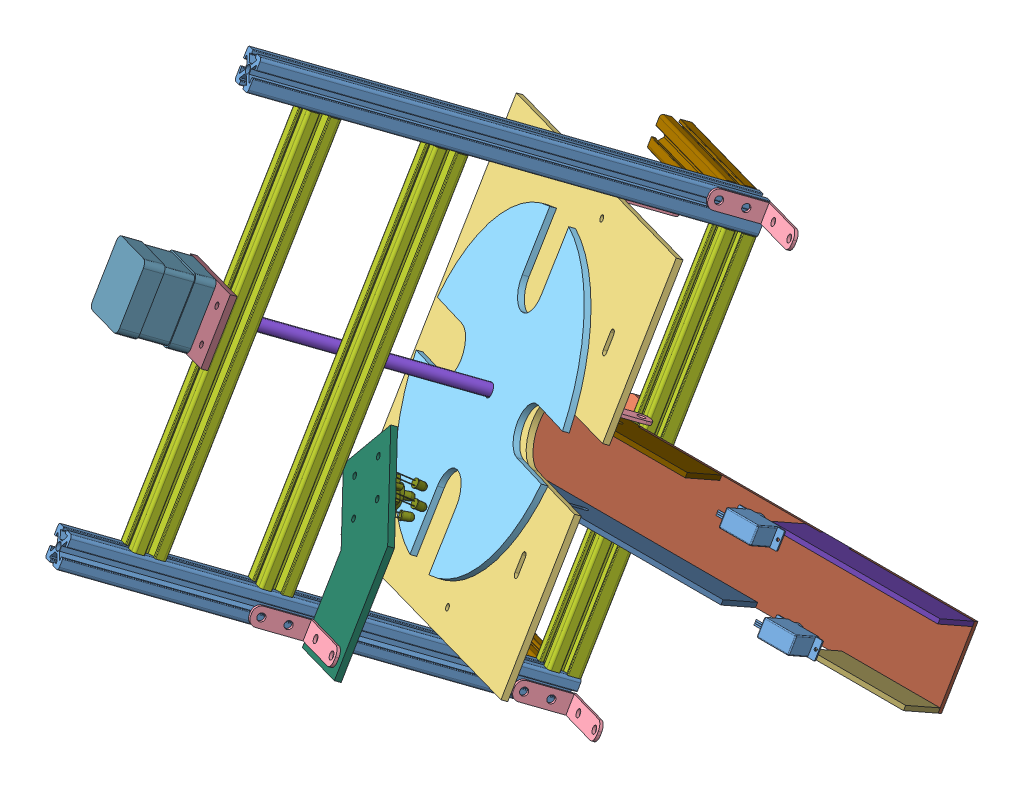
SolidWorks assembly Assem1, configuration Default. Lengths in mm.
Overall size (461.85 412.05 422.92).
30 component instances, 19 part files, 80 mates.
Components (placement in the parent):
- Nhom20x20x300-1: Nhom20x20x300 [Default] at (169.8417 109.2199 41.4005) x (-0.008301 -0.865395 0.501021) z (0.475419 -0.444204 -0.759381) size (20 20 300)
- Nhom20x20x300-2: Nhom20x20x300 [Default] at (171.9169 325.5687 -83.8548) x (-0.87972 -0.231892 -0.415113) z (0.475419 -0.444204 -0.759381) size (20 20 300)
- vongbi8mm-1: vongbi8mm [Default] at (293.7185 78.9174 -258.378) x (0.008301 0.865395 -0.501021) z (-0.475419 0.444204 0.759381) size (55 36 13)
- Part2-1: Part2 [Default] at (265.9386 118.0379 -191.2668) x (0.008301 0.865395 -0.501021) z (0.475419 -0.444204 -0.759381) size (250 250 4)
- Part3-3: Part3 [Default] at (266.9894 27.5581 -142.9497) x (-0.87972 -0.231892 -0.415113) z (0.475419 -0.444204 -0.759381) size (12 45 35)
- Part3-4: Part3 [Default] at (268.6911 204.9641 -245.659) x (0.87972 0.231892 0.415113) z (0.475419 -0.444204 -0.759381) size (12 45 35)
- Part1-1: Part1 [Default] at (238.4466 113.7027 -198.0415) x (0.879597 0.223435 0.419983) z (-0.475419 0.444204 0.759381) size (197.74 197.74 4)
- khop noi 5-8-1: khop noi 5-8 [Default] at (155.0404 192.1469 -65.0985) x (0.878303 0.289288 0.380651) z (0.475419 -0.444204 -0.759381) size (19.99 20 25)
- Nhom20x20x250-4: Nhom20x20x250 [Default] at (171.3298 305.0403 -119.3225) x (0.475419 -0.444204 -0.759381) z (-0.008301 -0.865395 0.501021) size (20 20 250)
- Part9-1: Part9 [Default] at (280.0757 75.3212 -264.8156) x (0.879293 0.211818 0.426587) z (-0.475419 0.444204 0.759381) size (8 8 250)
- Nhom20x20-3: Nhom20x20 [Default] at (197.2267 -60.2922 -211.0192) x (0.475419 -0.444204 -0.759381) z (0.87972 0.231892 0.415113) size (20 20 100)
- Nhom20x20-4: Nhom20x20 [Default] at (208.9763 164.4804 -361.4825) x (0.008301 0.865395 -0.501021) z (0.87972 0.231892 0.415113) size (20 20 100)
- Part3-10: Part3 [Default] at (321.9637 86.9359 -143.2658) x (0.87972 0.231892 0.415113) z (0.475419 -0.444204 -0.759381) size (12 45 35)
- Part3-13: Part3 [Default] at (322.8021 174.3408 -193.8689) x (-0.87972 -0.231892 -0.415113) z (0.475419 -0.444204 -0.759381) size (12 45 35)
- Part11-5: Part11 [Default] at (325.071 102.927 -166.4895) x (0.99957 -0.021278 -0.020192) z (-0.008301 -0.865395 0.501021) size (170 33 3)
- Part13-1: Part13 [Default] at (424.7125 111.6918 -195.6058) x (0.99957 -0.021278 -0.020192) z (0.028135 0.500638 0.865199) size (300 52 3)
- Part7-1: Part7 [Default] at (514.5672 91.3746 -183.304) x (0.99957 -0.021278 -0.020192) z (-0.008301 -0.865395 0.501021) size (70 33 3)
- Nhom20x20x250-5: Nhom20x20x250 [Default] at (206.8913 271.8136 -176.1245) x (0.475419 -0.444204 -0.759381) z (-0.008301 -0.865395 0.501021) size (20 20 250)
- Part3-14: Part3 [Default] at (334.4526 209.6405 -309.3432) x (-0.008301 -0.865395 0.501021) z (-0.475419 0.444204 0.759381) size (12 45 35)
- Part3-15: Part3 [Default] at (332.145 -30.9393 -170.0593) x (-0.008301 -0.865395 0.501021) z (-0.475419 0.444204 0.759381) size (12 45 35)
- Nhom20x20x250-6: Nhom20x20x250 [Default] at (296.9483 187.6696 -319.9712) x (0.87972 0.231892 0.415113) z (-0.008301 -0.865395 0.501021) size (20 20 250)
- Part8-2: Part8 [Default] at (152.5555 194.4686 -61.1294) x (-0.008301 -0.865395 0.501021) z (0.475419 -0.444204 -0.759381) size (42 62 4)
- Step1-2: Step1 [Default] at (132.5879 213.1252 -29.2354) x (0.008301 0.865395 -0.501021) z (0.475419 -0.444204 -0.759381) size (42 42 57)
- ban-2: ban [Default] at (232.1754 107.3064 -115.1813) x (-0.627926 -0.775899 0.060746) z (-0.475419 0.444204 0.759381) size (89.14 124.49 4)
- TCS3200 Sensor-3: TCS3200 Sensor [Default] at (241.4182 100.5871 -105.4642) x (0.616187 -0.447955 0.647805) z (0.627926 0.775899 -0.060746) size (33 28.07 33)
- Part3-16: Part3 [Default] at (258.6403 37.7392 -52.6514) x (-0.008301 -0.865395 0.501021) z (-0.475419 0.444204 0.759381) size (12 45 35)
- Part17-1: Part17 [Default] at (490.3505 140.8192 -196.1017) x (0.99957 -0.021278 -0.020192) z (-0.008301 -0.865395 0.501021) size (120 33 3)
- Part19-2: Part19 [Default] at (325.4778 145.3314 -191.0396) x (0.99957 -0.021278 -0.020192) z (-0.008301 -0.865395 0.501021) size (120 33 3)
- Hitec HS-55 Servo-6: Hitec HS-55 Servo [Default] at (499.0255 114.2412 -149.6535) x (0.008301 0.865395 -0.501021) z (-0.99957 0.021278 0.020192) size (11.6 27 33.7)
- Hitec HS-55 Servo-7: Hitec HS-55 Servo [Default] at (452.1716 150.2077 -168.9415) x (0.008301 0.865395 -0.501021) z (-0.99957 0.021278 0.020192) size (11.6 27 33.7)
Mates (geometry in assembly coordinates):
- Coincident35: coincident anti-aligned: plane of Nhom20x20x300-1 through (300.7606 -27.1272 -191.9378) normal (0.008301 0.865395 -0.501021); plane of Part2-1 through (178.8307 -15.1025 -173.188) normal (-0.008301 -0.865395 0.501021)
- Concentric5: concentric aligned: circle of Part2-1; circle of Part3-3
- Concentric6: concentric aligned: circle of Part2-1; circle of Part3-3
- Coincident45: coincident anti-aligned: plane of Part2-1 through (267.8403 116.2611 -194.3043) normal (0.475419 -0.444204 -0.759381); plane of Part3-3 through (266.9894 27.5581 -142.9497) normal (-0.475419 0.444204 0.759381)
- Coincident46: coincident anti-aligned: plane of Nhom20x20x300-1 through (310.708 -24.5051 -187.2439) normal (0.008301 0.865395 -0.501021); plane of Part3-3 through (262.4752 5.8069 -135.6861) normal (-0.008301 -0.865395 0.501021)
- Concentric7: concentric aligned: circle of Part2-1; circle of Part3-4
- Concentric8: concentric aligned: circle of Part2-1; circle of Part3-4
- Coincident47: coincident anti-aligned: plane of Part2-1 through (267.8403 116.2611 -194.3043) normal (0.475419 -0.444204 -0.759381); plane of Part3-4 through (268.6911 204.9641 -245.659) normal (-0.475419 0.444204 0.759381)
- Coincident48: coincident anti-aligned: plane of Nhom20x20x300-2 through (308.8245 190.8002 -314.3672) normal (-0.008301 -0.865395 0.501021); plane of Part3-4 through (275.107 224.9384 -255.9601) normal (0.008301 0.865395 -0.501021)
- Coincident83: coincident anti-aligned: plane of Nhom20x20x300-1 through (310.708 -24.5051 -187.2439) normal (0.008301 0.865395 -0.501021); plane of Nhom20x20x250-4 through (186.0404 91.9771 11.886) normal (-0.008301 -0.865395 0.501021)
- Coincident84: coincident aligned: plane of Nhom20x20x300-1 through (312.4135 -29.6664 -183.157) normal (0.87972 0.231892 0.415113); plane of Nhom20x20x250-4 through (187.7998 92.4409 12.7163) normal (0.87972 0.231892 0.415113)
- Coincident85: coincident anti-aligned: plane of Nhom20x20x300-2 through (308.8245 190.8002 -314.3672) normal (-0.008301 -0.865395 0.501021); plane of Nhom20x20x250-4 through (188.1156 308.3259 -113.3693) normal (0.008301 0.865395 -0.501021)
- Coincident86: coincident aligned: plane of Nhom20x20x300-2 through (314.5593 194.0382 -312.671) normal (0.87972 0.231892 0.415113); plane of Nhom20x20x250-4 through (187.7998 92.4409 12.7163) normal (0.87972 0.231892 0.415113)
- Concentric26: concentric anti-aligned: cylinder of vongbi8mm-1; cylinder of Part9-1 through (161.2209 186.3722 -74.9704) axis (0.475419 -0.444204 -0.759381) radius 4
- Coincident88: coincident aligned: plane of vongbi8mm-1 through (293.7185 78.9174 -258.378) normal (0.475419 -0.444204 -0.759381); plane of Part9-1 through (280.0757 75.3212 -264.8156) normal (0.475419 -0.444204 -0.759381)
- Concentric27: concentric aligned: cylinder of khop noi 5-8-1 through (160.2701 187.2606 -73.4517) axis (0.475419 -0.444204 -0.759381) radius 4; cylinder of Part9-1 through (161.2209 186.3722 -74.9704) axis (0.475419 -0.444204 -0.759381) radius 4
- Coincident89: coincident aligned: plane of khop noi 5-8-1 through (152.4379 183.4794 -78.777) normal (-0.475419 0.444204 0.759381); plane of Part9-1 through (161.2209 186.3722 -74.9704) normal (-0.475419 0.444204 0.759381)
- Coincident101: coincident anti-aligned: plane of Nhom20x20x300-1 through (294.761 -40.362 -187.9521) normal (-0.87972 -0.231892 -0.415113); plane of Nhom20x20-3 through (286.2989 -22.4143 -180.045) normal (0.87972 0.231892 0.415113)
- Coincident102: coincident aligned: plane of Nhom20x20x300-1 through (296.4665 -45.5233 -183.8653) normal (-0.008301 -0.865395 0.501021); plane of Nhom20x20-3 through (288.2889 -39.9903 -174.4439) normal (-0.008301 -0.865395 0.501021)
- Coincident103: coincident aligned: plane of Nhom20x20x300-1 through (296.6159 -29.9462 -192.8837) normal (0.475419 -0.444204 -0.759381); plane of Nhom20x20-3 through (294.7735 -39.0574 -188.7074) normal (0.475419 -0.444204 -0.759381)
- Coincident104: coincident anti-aligned: plane of Nhom20x20x300-2 through (297.0148 194.5993 -323.9832) normal (-0.87972 -0.231892 -0.415113); plane of Nhom20x20-4 through (288.4073 197.3961 -307.3044) normal (0.87972 0.231892 0.415113)
- Coincident105: coincident aligned: plane of Nhom20x20x300-2 through (312.9327 207.4208 -321.5176) normal (0.475419 -0.444204 -0.759381); plane of Nhom20x20-4 through (297.0977 203.2467 -328.9896) normal (0.475419 -0.444204 -0.759381)
- Coincident106: coincident aligned: plane of Nhom20x20x300-2 through (302.8325 206.4848 -327.2934) normal (0.008301 0.865395 -0.501021); plane of Nhom20x20-4 through (293.3074 208.5345 -323.9109) normal (0.008301 0.865395 -0.501021)
- Concentric31: concentric anti-aligned: cylinder of Part2-1 through (319.9168 73.5683 -131.4604) axis (0.475419 -0.444204 -0.759381) radius 2.5; cylinder of Part3-10 through (322.7693 70.9031 -136.0167) axis (-0.475419 0.444204 0.759381) radius 2.5
- Coincident128: coincident anti-aligned: plane of Part2-1 through (267.8403 116.2611 -194.3043) normal (0.475419 -0.444204 -0.759381); plane of Part3-10 through (321.9637 86.9359 -143.2658) normal (-0.475419 0.444204 0.759381)
- Concentric32: concentric aligned: circle of Part2-1; circle of Part3-13
- Coincident153: coincident anti-aligned: plane of Part2-1 through (267.8403 116.2611 -194.3043) normal (0.475419 -0.444204 -0.759381); plane of Part3-13 through (322.8021 174.3408 -193.8689) normal (-0.475419 0.444204 0.759381)
- Parallel23: parallel anti-aligned: plane of Part3-10 through (328.3797 106.9103 -153.5668) normal (0.008301 0.865395 -0.501021); plane of Part3-13 through (318.2879 152.5897 -186.6054) normal (-0.008301 -0.865395 0.501021)
- Coincident161: coincident anti-aligned: plane of Part3-10 through (328.3797 106.9103 -153.5668) normal (0.008301 0.865395 -0.501021); plane of Part11-5 through (325.0461 100.3308 -164.9865) normal (-0.008301 -0.865395 0.501021)
- Coincident162: coincident anti-aligned: plane of Part2-1 through (267.8403 116.2611 -194.3043) normal (0.475419 -0.444204 -0.759381); plane of Part11-5 through (273.5214 -23.3186 -109.0996) normal (-0.475419 0.444204 0.759381)
- Coincident163: coincident: plane of Part3-10 through (328.3797 106.9103 -153.5668) normal (0.87972 0.231892 0.415113); line of Part11-5 through (327.4288 107.7987 -152.0481) axis (0.008301 0.865395 -0.501021)
- Coincident170: coincident anti-aligned: plane of Part11-5 through (374.6026 91.7574 -178.9741) normal (-0.028135 -0.500638 -0.865199); plane of Part13-1 through (424.7969 113.1937 -193.0102) normal (0.028135 0.500638 0.865199)
- Coincident171: coincident aligned: plane of Part11-5 through (325.0461 100.3308 -164.9865) normal (-0.008301 -0.865395 0.501021); plane of Part13-1 through (574.5165 87.5018 -183.0125) normal (-0.008301 -0.865395 0.501021)
- Coincident172: coincident anti-aligned: plane of Part11-5 through (334.5354 91.1066 -180.762) normal (0.99957 -0.021278 -0.020192); plane of Part13-1 through (334.3634 90.1983 -188.3214) normal (-0.99957 0.021278 0.020192)
- Coincident182: coincident anti-aligned: plane of Part13-1 through (424.7969 113.1937 -193.0102) normal (0.028135 0.500638 0.865199); plane of Part7-1 through (574.5165 87.5018 -183.0125) normal (-0.028135 -0.500638 -0.865199)
- Coincident183: coincident anti-aligned: plane of Part13-1 through (534.2773 85.9427 -192.3598) normal (-0.99957 0.021278 0.020192); plane of Part7-1 through (534.5337 88.3529 -182.2048) normal (0.99957 -0.021278 -0.020192)
- Coincident184: coincident aligned: plane of Part13-1 through (574.5165 87.5018 -183.0125) normal (-0.008301 -0.865395 0.501021); plane of Part7-1 through (514.5423 88.7784 -181.8009) normal (-0.008301 -0.865395 0.501021)
- Concentric34: concentric aligned: circle of Part2-1; cylinder of Part9-1 through (161.2209 186.3722 -74.9704) axis (0.475419 -0.444204 -0.759381) radius 4
- Coincident208: coincident anti-aligned: plane of Nhom20x20x300-1 through (310.708 -24.5051 -187.2439) normal (0.008301 0.865395 -0.501021); plane of Nhom20x20x250-5 through (221.6019 58.7505 -44.9159) normal (-0.008301 -0.865395 0.501021)
- Coincident209: coincident aligned: plane of Nhom20x20x300-1 through (312.4135 -29.6664 -183.157) normal (0.87972 0.231892 0.415113); plane of Nhom20x20x250-5 through (223.3614 59.2143 -44.0857) normal (0.87972 0.231892 0.415113)
- Coincident210: coincident aligned: plane of Nhom20x20x300-2 through (314.5593 194.0382 -312.671) normal (0.87972 0.231892 0.415113); plane of Nhom20x20x250-5 through (223.3614 59.2143 -44.0857) normal (0.87972 0.231892 0.415113)
- Coincident215: coincident anti-aligned: plane of Nhom20x20x300-2 through (314.6532 203.8237 -318.3363) normal (0.87972 0.231892 0.415113); plane of Part3-14 through (313.6583 200.119 -314.1584) normal (-0.87972 -0.231892 -0.415113)
- Coincident216: coincident aligned: plane of Nhom20x20x300-2 through (312.9493 209.1516 -322.5196) normal (0.008301 0.865395 -0.501021); plane of Part3-14 through (313.7579 210.5038 -320.1707) normal (0.008301 0.865395 -0.501021)
- Coincident217: coincident aligned: plane of Nhom20x20x300-2 through (312.9327 207.4208 -321.5176) normal (0.475419 -0.444204 -0.759381); plane of Part3-14 through (334.4526 209.6405 -309.3432) normal (0.475419 -0.444204 -0.759381)
- Coincident218: coincident anti-aligned: plane of Nhom20x20x300-1 through (312.3181 -39.6185 -177.3953) normal (0.87972 0.231892 0.415113); plane of Part3-15 through (311.3506 -40.4608 -174.8745) normal (-0.87972 -0.231892 -0.415113)
- Coincident219: coincident aligned: plane of Nhom20x20x300-1 through (296.6159 -29.9462 -192.8837) normal (0.475419 -0.444204 -0.759381); plane of Part3-15 through (332.145 -30.9393 -170.0593) normal (0.475419 -0.444204 -0.759381)
- Coincident220: coincident aligned: plane of Nhom20x20x300-1 through (305.2571 -43.2061 -179.7173) normal (-0.008301 -0.865395 0.501021); plane of Part3-15 through (311.3506 -40.4608 -174.8745) normal (-0.008301 -0.865395 0.501021)
- Coincident221: coincident aligned: plane of Nhom20x20x300-1 through (296.6159 -29.9462 -192.8837) normal (0.475419 -0.444204 -0.759381); plane of Nhom20x20x300-2 through (312.9327 207.4208 -321.5176) normal (0.475419 -0.444204 -0.759381)
- Coincident227: coincident anti-aligned: plane of Nhom20x20x300-1 through (310.708 -24.5051 -187.2439) normal (0.008301 0.865395 -0.501021); plane of Nhom20x20x250-6 through (288.075 -20.2197 -180.2168) normal (-0.008301 -0.865395 0.501021)
- Coincident229: coincident: line of Nhom20x20x300-1 through (312.4135 -29.6664 -183.157) axis (-0.475419 0.444204 0.759381); plane of Nhom20x20x250-6 through (303.9099 -16.0457 -172.7448) normal (0.87972 0.231892 0.415113)
- Coincident230: coincident aligned: plane of Nhom20x20x300-1 through (296.6159 -29.9462 -192.8837) normal (0.475419 -0.444204 -0.759381); plane of Nhom20x20x250-6 through (310.708 -24.5051 -187.2439) normal (0.475419 -0.444204 -0.759381)
- Coincident231: coincident anti-aligned: plane of vongbi8mm-1 through (289.7302 85.2699 -247.4716) normal (0.87972 0.231892 0.415113); plane of Nhom20x20x250-6 through (293.9222 -27.7908 -193.1972) normal (-0.87972 -0.231892 -0.415113)
- Coincident232: coincident aligned: plane of vongbi8mm-1 through (293.7185 78.9174 -258.378) normal (0.475419 -0.444204 -0.759381); plane of Nhom20x20x250-6 through (300.5913 -27.1719 -192.0177) normal (0.475419 -0.444204 -0.759381)
- Concentric44: concentric aligned: cylinder of khop noi 5-8-1 through (166.9259 181.0418 -84.083) axis (-0.475419 0.444204 0.759381) radius 2.5; cylinder of Part8-2 through (154.4572 192.6918 -64.1669) axis (-0.475419 0.444204 0.759381) radius 4
- Coincident248: coincident anti-aligned: plane of Nhom20x20x250-4 through (171.014 89.1553 6.763) normal (-0.475419 0.444204 0.759381); plane of Part8-2 through (154.4572 192.6918 -64.1669) normal (0.475419 -0.444204 -0.759381)
- Parallel24: parallel aligned: plane of Nhom20x20x250-4 through (187.7998 92.4409 12.7163) normal (0.87972 0.231892 0.415113); plane of Part8-2 through (188.6241 203.9762 -44.1098) normal (0.87972 0.231892 0.415113)
- Concentric45: concentric aligned: cylinder of khop noi 5-8-1 through (166.9259 181.0418 -84.083) axis (-0.475419 0.444204 0.759381) radius 2.5; cylinder of Step1-2 through (159.6868 187.8056 -72.5201) axis (-0.475419 0.444204 0.759381) radius 2.5
- Coincident250: coincident anti-aligned: plane of Part8-2 through (152.5555 194.4686 -61.1294) normal (-0.475419 0.444204 0.759381); plane of Step1-2 through (167.3697 183.6991 -45.5551) normal (0.475419 -0.444204 -0.759381)
- Coincident251: coincident aligned: plane of Part8-2 through (135.8088 169.6488 -62.3628) normal (-0.87972 -0.231892 -0.415113); plane of Step1-2 through (128.2353 180.2177 -52.2168) normal (-0.87972 -0.231892 -0.415113)
- Coincident258: coincident anti-aligned: plane of Nhom20x20x300-1 through (312.3181 -39.6185 -177.3953) normal (0.87972 0.231892 0.415113); plane of ban-2 through (239.2231 71.7676 -84.7129) normal (-0.87972 -0.231892 -0.415113)
- Concentric47: concentric anti-aligned: cylinder of ban-2 through (239.6633 117.6621 -111.2836) axis (0.475419 -0.444204 -0.759381) radius 2; cylinder of TCS3200 Sensor-3 through (242.3256 115.1746 -115.5361) axis (-0.475419 0.444204 0.759381) radius 2
- Coincident261: coincident aligned: circle of ban-2; cylinder of TCS3200 Sensor-3 through (242.0322 84.5782 -97.8224) axis (-0.475419 0.444204 0.759381) radius 2
- Coincident262: coincident anti-aligned: plane of ban-2 through (232.1754 107.3064 -115.1813) normal (0.475419 -0.444204 -0.759381); plane of TCS3200 Sensor-3 through (241.4182 100.5871 -105.4642) normal (-0.475419 0.444204 0.759381)
- Coincident265: coincident anti-aligned: cylinder of ban-2 through (252.0424 36 -55.7647) axis (0.475419 -0.444204 -0.759381) radius 2.5; circle of Part3-16
- Coincident266: coincident: plane of ban-2 through (230.2738 109.0832 -112.1438) normal (-0.475419 0.444204 0.759381); line of Part3-16 through (238.7968 27.3292 -58.9853) axis (0.87972 0.231892 0.415113)
- Parallel27: parallel aligned: plane of ban-2 through (282.7496 35.4622 -36.2256) normal (-0.008301 -0.865395 0.501021); plane of Part3-16 through (237.846 28.2176 -57.4665) normal (-0.008301 -0.865395 0.501021)
- Coincident269: coincident anti-aligned: plane of Nhom20x20x300-1 through (312.3181 -39.6185 -177.3953) normal (0.87972 0.231892 0.415113); plane of Part3-16 through (237.846 28.2176 -57.4665) normal (-0.87972 -0.231892 -0.415113)
- Coincident272: coincident anti-aligned: plane of Part13-1 through (424.7969 113.1937 -193.0102) normal (0.028135 0.500638 0.865199); plane of Part17-1 through (574.9233 129.9061 -207.5625) normal (-0.028135 -0.500638 -0.865199)
- Coincident273: coincident aligned: plane of Part13-1 through (574.5165 87.5018 -183.0125) normal (0.99957 -0.021278 -0.020192); plane of Part17-1 through (575.7673 144.9253 -181.6065) normal (0.99957 -0.021278 -0.020192)
- Coincident274: coincident aligned: plane of Part13-1 through (574.9482 132.5023 -209.0656) normal (0.008301 0.865395 -0.501021); plane of Part17-1 through (490.3505 140.8192 -196.1017) normal (0.008301 0.865395 -0.501021)
- Coincident293: coincident anti-aligned: plane of Part13-1 through (424.7969 113.1937 -193.0102) normal (0.028135 0.500638 0.865199); plane of Part19-2 through (375.0093 134.1617 -203.5241) normal (-0.028135 -0.500638 -0.865199)
- Coincident294: coincident anti-aligned: plane of Part2-1 through (267.8403 116.2611 -194.3043) normal (0.475419 -0.444204 -0.759381); plane of Part19-2 through (273.9282 19.0858 -133.6497) normal (-0.475419 0.444204 0.759381)
- Coincident295: coincident aligned: plane of Part13-1 through (574.9482 132.5023 -209.0656) normal (0.008301 0.865395 -0.501021); plane of Part19-2 through (325.4778 145.3314 -191.0396) normal (0.008301 0.865395 -0.501021)
- Parallel32: parallel aligned: plane of Part2-1 through (180.9059 201.2463 -298.4433) normal (0.008301 0.865395 -0.501021); plane of Part19-2 through (325.4778 145.3314 -191.0396) normal (0.008301 0.865395 -0.501021)
- Parallel33: parallel: line of Part2-1 through (352.873 33.0527 -87.1279) axis (-0.87972 -0.231892 -0.415113); plane of Part11-5 through (325.0461 100.3308 -164.9865) normal (-0.008301 -0.865395 0.501021)
- Coincident298: coincident aligned: plane of Part7-1 through (514.5423 88.7784 -181.8009) normal (-0.008301 -0.865395 0.501021); plane of Hitec HS-55 Servo-6 through (498.9774 109.2219 -146.7476) normal (-0.008301 -0.865395 0.501021)
- Coincident299: coincident anti-aligned: plane of Part7-1 through (505.3907 104.0104 -155.643) normal (0.028135 0.500638 0.865199); plane of Hitec HS-55 Servo-6 through (498.7406 109.1722 -158.4137) normal (-0.028135 -0.500638 -0.865199)
- Coincident300: coincident aligned: plane of Part17-1 through (490.3505 140.8192 -196.1017) normal (0.008301 0.865395 -0.501021); plane of Hitec HS-55 Servo-7 through (452.2198 155.227 -171.8474) normal (0.008301 0.865395 -0.501021)
- Coincident301: coincident anti-aligned: plane of Part17-1 through (455.8189 147.4786 -179.1835) normal (0.028135 0.500638 0.865199); plane of Hitec HS-55 Servo-7 through (451.8868 145.1387 -177.7017) normal (-0.028135 -0.500638 -0.865199)
- Coincident306: coincident aligned: plane of Nhom20x20x300-1 through (305.2571 -43.2061 -179.7173) normal (-0.008301 -0.865395 0.501021); plane of Part3-16 through (237.846 28.2176 -57.4665) normal (-0.008301 -0.865395 0.501021)
